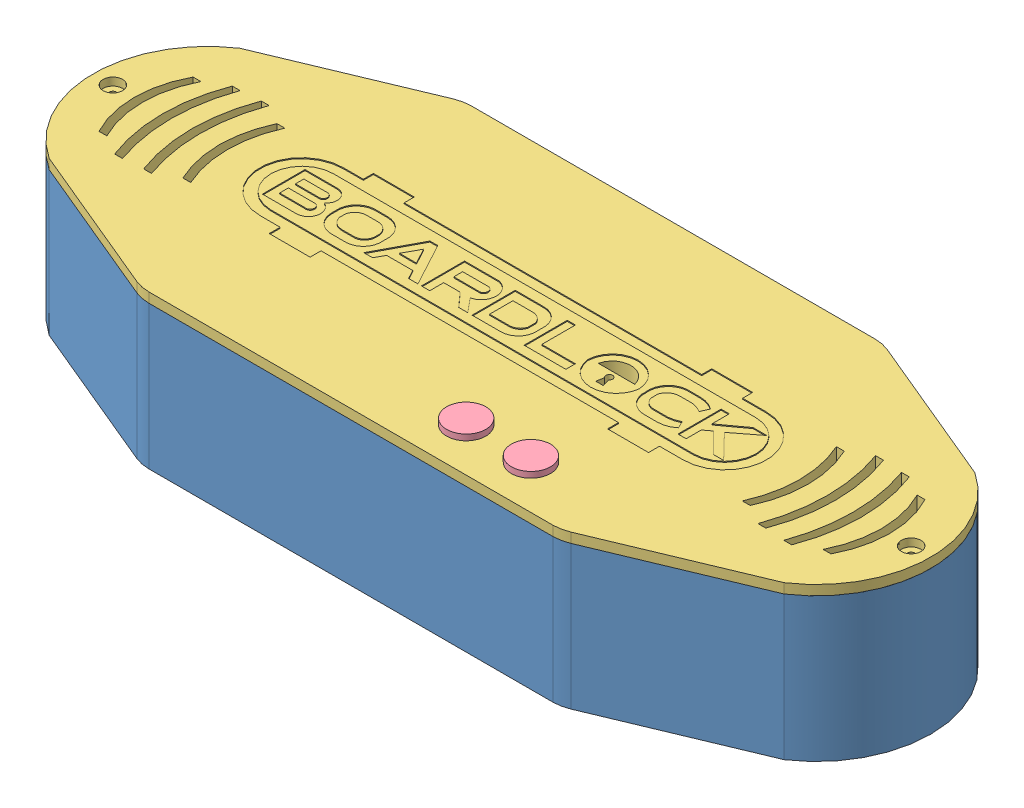
SolidWorks assembly BL_v3, configuration Default. Lengths in mm.
Overall size (213.95 40.6 82.2).
5 component instances, 4 part files, 6 mates.
Components (placement in the parent):
- BL_Base_v3-1: BL_Base_v3 [Default] at (17.1966 81.1072 142.0148) size (213.6 36.6 82.2)
- Speaker_Holder-1: Speaker_Holder [Default] at (17.1966 106.1072 142.0148) size (53.65 28.5 77.2)
- BL_Top_v3-1: BL_Top_v3 [Default] at (17.1966 114.2072 142.0148) size (213.6 5 82.2)
- BL_Button_Rod_v3-1: BL_Button_Rod_v3 [Default] at (103.0266 100.7072 210.6148) size (10 17.5 10)
- BL_Button_Rod_v3-2: BL_Button_Rod_v3 [Default] at (86.5166 100.7072 210.6148) size (10 17.5 10)
Mates (geometry in assembly coordinates):
- Coincident1: coincident anti-aligned: line of BL_Base_v3-1 through (121.6966 80.1072 184.2148) axis (0 0 1); line of Speaker_Holder-1 through (121.6966 80.1072 219.2148) axis (0 0 -1)
- Coincident2: coincident anti-aligned: line of BL_Base_v3-1 through (121.6966 80.1072 219.2148) axis (0.924565 0 -0.381024); line of Speaker_Holder-1 through (126.6966 80.1072 217.1542) axis (-0.924565 0 0.381024)
- Coincident3: coincident: line of BL_Base_v3-1 through (16.6995 114.2072 139.5148) axis (1 0 0); line of BL_Top_v3-1 through (16.6995 114.2072 139.5148) axis (1 0 0)
- Coincident4: coincident aligned: line of BL_Base_v3-1 through (123.545 114.2072 220.9435) axis (0.922869 0 -0.385115); line of BL_Top_v3-1 through (123.545 114.2072 220.9435) axis (0.922869 0 -0.385115)
- Coincident5: coincident aligned: circle of BL_Top_v3-1; circle of BL_Button_Rod_v3-1
- Coincident6: coincident aligned: circle of BL_Top_v3-1; circle of BL_Button_Rod_v3-2
